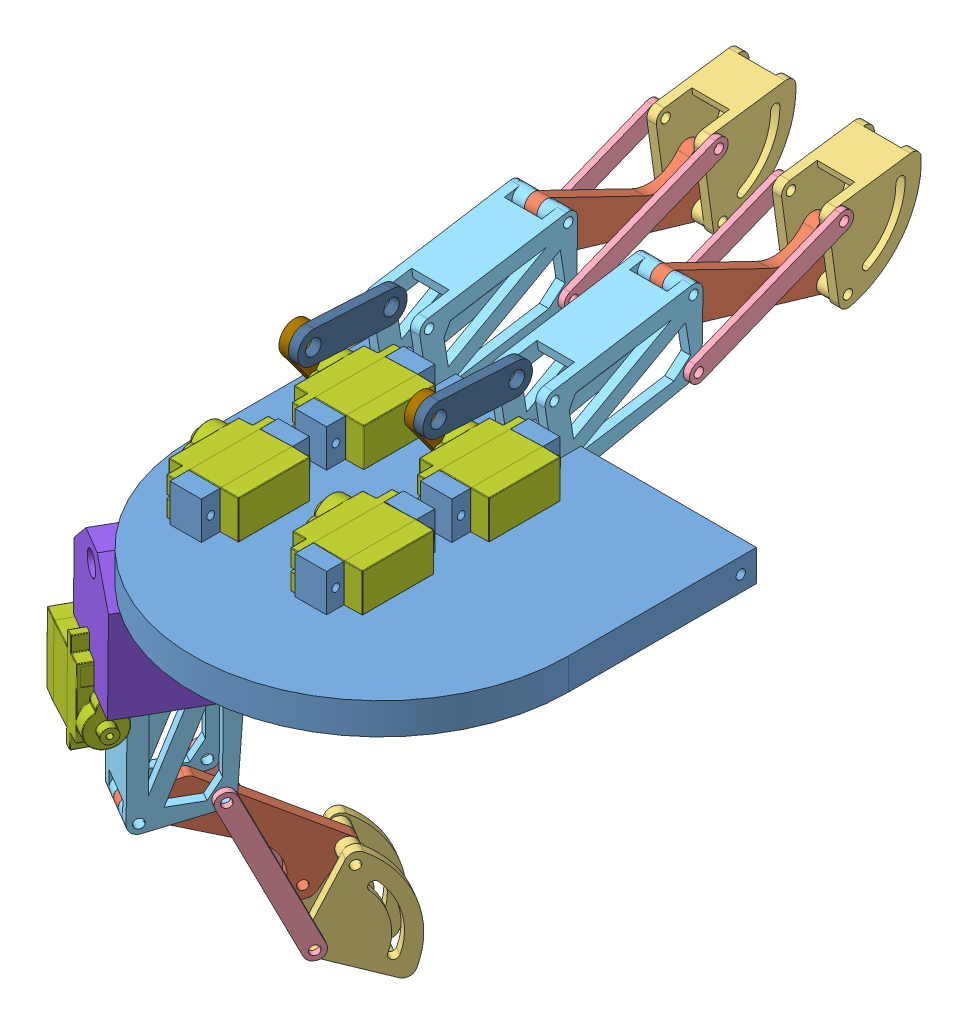
SolidWorks assembly hand, configuration Default. Lengths in mm.
Overall size (148.74 231.01 238.42).
30 component instances, 10 part files, 36 mates.
Components (placement in the parent):
- base-1: base [Default] at (16.5956 -11.2965 -4.4795) size (120 40 120)
- assembly-1: assembly [Default] at (10.0312 9.6394 -110.1816) x (0 -0.749901 -0.66155) z (1 0 0) size (97.15 111.4 22) (flexible)
  - [F1]ProximalPhalange-1: [F1]ProximalPhalange [Default] at (-2.4835 -4.9748 -0.4592) x (0.84704 0.531528 0) z (0 0 1) size (60.17 20 4)
  - [F1]DistalPhalange_Joint-1: [F1]DistalPhalange_Joint [Default] at (11.4723 33.8281 -7.4592) x (0.552506 0.833509 0) z (0 0 1) size (29.83 29.83 18)
  - [F1]MedialPhalange_Lever-1: [F1]MedialPhalange_Lever [Default] at (7.2551 11.1157 -9.4592) x (0.335009 0.942215 0) z (0 0 1) size (56 6 2)
  - [F1]MedialPhalange-1: [F1]MedialPhalange [Default] at (-40.1872 -36.8079 -7.4592) x (0.534366 0.845253 0) z (0 0 1) size (51 28 18)
  - [F1]MedialPhalange_Lever-2: [F1]MedialPhalange_Lever [Default] at (7.2551 11.1157 10.5408) x (0.335009 0.942215 0) z (0 0 1) size (56 6 2)
- assembly-2: assembly [Default] at (-29.9688 9.6845 -110.1674) x (0 -0.749313 -0.662216) z (1 0 0) size (97.15 111.4 22) (flexible)
  - [F1]ProximalPhalange-1: [F1]ProximalPhalange [Default] at (-2.4835 -4.9748 -0.4592) x (0.84704 0.531528 0) z (0 0 1) size (60.17 20 4)
  - [F1]DistalPhalange_Joint-1: [F1]DistalPhalange_Joint [Default] at (11.4723 33.8281 -7.4592) x (0.552506 0.833509 0) z (0 0 1) size (29.83 29.83 18)
  - [F1]MedialPhalange_Lever-1: [F1]MedialPhalange_Lever [Default] at (7.2551 11.1157 -9.4592) x (0.335009 0.942215 0) z (0 0 1) size (56 6 2)
  - [F1]MedialPhalange-1: [F1]MedialPhalange [Default] at (-40.1872 -36.8079 -7.4592) x (0.534366 0.845253 0) z (0 0 1) size (51 28 18)
  - [F1]MedialPhalange_Lever-2: [F1]MedialPhalange_Lever [Default] at (7.2551 11.1157 10.5408) x (0.335009 0.942215 0) z (0 0 1) size (56 6 2)
- assembly-3: assembly [Default] at (-37.6816 -101.2528 1.716) x (0.4097 -0.534158 -0.739474) z (-0.865687 0.027933 -0.499805) size (112.15 71.63 22) (flexible)
  - [F1]ProximalPhalange-1: [F1]ProximalPhalange [Default] at (-7.8164 -11.2497 -0.4592) x (0.999991 0.004269 0) z (0 0 1) size (60.17 20 4)
  - [F1]DistalPhalange_Joint-1: [F1]DistalPhalange_Joint [Default] at (38.2009 18.1184 -7.4592) x (0.992825 -0.119578 0) z (0 0 1) size (29.83 29.83 18)
  - [F1]MedialPhalange_Lever-1: [F1]MedialPhalange_Lever [Default] at (19.8503 1.1708 -9.4592) x (0.838815 0.544416 0) z (0 0 1) size (56 6 2)
  - [F1]MedialPhalange-1: [F1]MedialPhalange [Default] at (-40.1872 -36.8079 -7.4592) x (0.534366 0.845253 0) z (0 0 1) size (51 28 18)
  - [F1]MedialPhalange_Lever-2: [F1]MedialPhalange_Lever [Default] at (19.8503 1.1708 10.5408) x (0.838815 0.544416 0) z (0 0 1) size (56 6 2)
- servo_motor.ipt-2: servo_motor.ipt [Default] at (-13.0981 -31.2965 -49.4741) x (0 -1 0) z (-0.866025 0 -0.5) size (21.76 46 55)
- TowerPro SG92R Servo Motor-2: TowerPro SG92R Servo Motor [Default] at (-23.4044 4.7035 -34.6979) x (0 0 -1) z (0 1 0) size (32.49 29.58 12.43)
- TowerPro SG92R Servo Motor-3: TowerPro SG92R Servo Motor [Default] at (-23.4044 4.7035 5.3021) x (0 0 -1) z (0 1 0) size (32.49 29.58 12.43)
- TowerPro SG92R Servo Motor-4: TowerPro SG92R Servo Motor [Default] at (16.5956 4.7035 -34.6979) x (0 0 -1) z (0 1 0) size (32.49 29.58 12.43)
- TowerPro SG92R Servo Motor-5: TowerPro SG92R Servo Motor [Default] at (16.5956 4.7035 5.7389) x (0 0 -1) z (0 1 0) size (32.49 29.58 12.43)
- joint-1: joint [Default] at (-25.6367 -39.8449 -8.7932) x (-0.865687 0.027933 -0.499805) z (-0.5 0 0.866025) size (30 40.08 40)
- TowerPro SG92R Servo Motor-6: TowerPro SG92R Servo Motor [Default] at (-48.3775 -57.6939 22.4871) x (-0.024191 -0.99961 -0.013967) z (-0.477168 -0.000731 0.878812) size (32.49 29.58 12.43)
- bar1-1: bar1 [Default] at (-37.428 10.7264 -35.4787) x (0 0.803059 0.5959) z (1 0 0) size (25 10 3)
- bar1-2: bar1 [Default] at (2.572 10.7338 -35.4886) x (0 -0.804043 -0.594571) z (1 0 0) size (25 10 3)
- bar2-1: bar2 [Default] at (8.572 16.0948 -43.5114) x (0 0.053544 0.998566) z (-1 0 0) size (35 10 3)
- bar2-2: bar2 [Default] at (-31.428 16.0859 -43.4918) x (0 0.053078 0.99859) z (-1 0 0) size (35 10 3)
Mates (geometry in assembly coordinates):
- Concentric1: concentric aligned: cylinder of base-1 through (76.5956 -6.2965 -59.4795) axis (-1 0 0) radius 1.5; cylinder of assembly-1/[F1]MedialPhalange-1 through (5.572 -6.2965 -59.4795) axis (-1 0 0) radius 1.5
- Concentric2: concentric aligned: cylinder of base-1 through (-13.4044 4.7035 -48.7695) axis (-1 0 0) radius 1.25; cylinder of TowerPro SG92R Servo Motor-2 through (-18.2615 4.7035 -48.7695) axis (-1 0 0) radius 1.016
- Coincident1: coincident anti-aligned: plane of base-1 through (-23.4044 -11.2965 -4.4795) normal (-1 0 0); plane of TowerPro SG92R Servo Motor-2 through (-23.4044 4.7035 -34.6979) normal (1 0 0)
- Parallel1: parallel aligned: line of base-1 through (-23.4044 10.7035 -45.7695) axis (0 0 -1); line of TowerPro SG92R Servo Motor-2 through (-23.4044 10.7423 -45.8422) axis (0 0 -1)
- Concentric3: concentric aligned: cylinder of base-1 through (-13.4044 4.7035 -8.7695) axis (-1 0 0) radius 1.25; cylinder of TowerPro SG92R Servo Motor-3 through (-18.2615 4.7035 -8.7695) axis (-1 0 0) radius 1.016
- Coincident3: coincident anti-aligned: plane of base-1 through (-23.4044 -11.2965 35.5205) normal (-1 0 0); plane of TowerPro SG92R Servo Motor-3 through (-23.4044 4.7035 5.3021) normal (1 0 0)
- Parallel2: parallel anti-aligned: line of base-1 through (-23.4044 10.7035 -5.7695) axis (0 0 -1); line of TowerPro SG92R Servo Motor-3 through (-23.4044 10.7423 -5.8422) axis (0 0 1)
- Concentric4: concentric aligned: cylinder of base-1 through (26.5956 4.7035 -48.7695) axis (-1 0 0) radius 1.25; cylinder of TowerPro SG92R Servo Motor-4 through (21.7385 4.7035 -48.7695) axis (-1 0 0) radius 1.016
- Coincident5: coincident anti-aligned: plane of base-1 through (16.5956 -11.2965 -4.4795) normal (-1 0 0); plane of TowerPro SG92R Servo Motor-4 through (16.5956 4.7035 -34.6979) normal (1 0 0)
- Parallel3: parallel: line of base-1 through (16.5956 10.7035 -45.7695) axis (0 0 -1); plane of TowerPro SG92R Servo Motor-4 through (16.5956 10.7423 -34.6979) normal (-0.026177 0.999657 0)
- Concentric5: concentric aligned: cylinder of base-1 through (26.5956 4.7035 19.8105) axis (-1 0 0) radius 1.25; cylinder of TowerPro SG92R Servo Motor-5 through (21.7385 4.7035 19.8105) axis (-1 0 0) radius 1.016
- Coincident7: coincident anti-aligned: plane of base-1 through (16.5956 -11.2965 35.5205) normal (-1 0 0); plane of TowerPro SG92R Servo Motor-5 through (16.5956 4.7035 5.7389) normal (1 0 0)
- Parallel4: parallel anti-aligned: line of base-1 through (16.5956 10.7035 -5.7695) axis (0 0 -1); line of TowerPro SG92R Servo Motor-5 through (16.5956 10.7423 -5.4054) axis (0 0 1)
- Concentric6: concentric aligned: cylinder of base-1 through (76.5956 -6.2965 -59.4795) axis (-1 0 0) radius 1.5; cylinder of assembly-2/[F1]MedialPhalange-1 through (-34.428 -6.2965 -59.4795) axis (-1 0 0) radius 1.5
- Coincident9: coincident anti-aligned: plane of assembly-2/[F1]MedialPhalange-1 through (-34.428 2.2861 -100.1045) normal (1 0 0); plane of TowerPro SG92R Servo Motor-2 through (-34.428 4.7035 -34.6979) normal (-1 0 0)
- Coincident10: coincident anti-aligned: plane of assembly-1/[F1]MedialPhalange-1 through (5.572 2.2499 -100.1121) normal (1 0 0); plane of TowerPro SG92R Servo Motor-4 through (5.572 4.7035 -34.6979) normal (-1 0 0)
- Coincident11: coincident anti-aligned: plane of base-1 through (-36.9527 -29.2965 -31.4923) normal (-0.5 0 0.866025); plane of servo_motor.ipt-2 through (11.3653 -21.2965 -3.5959) normal (0.5 0 -0.866025)
- Coincident12: coincident anti-aligned: plane of base-1 through (16.5956 -11.2965 -4.4795) normal (0 -1 0); plane of servo_motor.ipt-2 through (21.9759 -11.2965 -29.2241) normal (0 1 0)
- Coincident13: coincident anti-aligned: plane of base-1 through (-26.8481 -29.2965 -25.6584) normal (0.866025 0 0.5); plane of servo_motor.ipt-2 through (-13.0981 -11.2965 -49.4741) normal (-0.866025 0 -0.5)
- Concentric7: concentric aligned: cylinder of servo_motor.ipt-2 through (-25.4379 -21.2965 -8.1011) axis (0.5 0 -0.866025) radius 3; cylinder of joint-1 through (-45.1879 -21.2965 26.1069) axis (0.5 0 -0.866025) radius 3.6171
- Coincident14: coincident anti-aligned: plane of servo_motor.ipt-2 through (-25.1879 -21.2965 -8.5341) normal (-0.5 0 0.866025); plane of joint-1 through (-25.6367 -39.8449 -8.7932) normal (0.5 0 -0.866025)
- Concentric8: concentric anti-aligned: cylinder of assembly-3/[F1]MedialPhalange-1 through (-28.699 -48.8112 -1.9896) axis (0.865687 -0.027933 0.499805) radius 1.5; cylinder of joint-1 through (-42.55 -48.3643 -9.9865) axis (-0.865687 0.027933 -0.499805) radius 2.5
- Distance1: distance = 1 mm aligned: plane of joint-1 through (-58.9849 -54.4201 18.1412) normal (-0.865687 0.027933 -0.499805); plane of assembly-3/[F1]MedialPhalange-1 through (-43.6875 -89.8495 -8.3339) normal (-0.865687 0.027933 -0.499805)
- Parallel5: parallel anti-aligned: plane of assembly-3/[F1]MedialPhalange-1 through (-28.6264 -45.8124 -1.9477) normal (0.024191 0.99961 0.013967); plane of joint-1 through (-33.0143 -55.2581 33.1354) normal (-0.024191 -0.99961 -0.013967)
- Coincident17: coincident anti-aligned: plane of assembly-3/[F1]MedialPhalange-1 through (-41.199 -48.8112 19.661) normal (-0.5 0 0.866025); plane of TowerPro SG92R Servo Motor-6 through (-45.496 -57.6895 17.1801) normal (0.5 0 -0.866025)
- Distance3: distance = 5 mm: line of TowerPro SG92R Servo Motor-6 through (-64.7414 -46.0403 20.5769) axis (-0.024191 -0.99961 -0.013967); plane of assembly-3/[F1]MedialPhalange-1 through (-43.6875 -89.8495 -8.3339) normal (-0.865687 0.027933 -0.499805)
- Concentric9: concentric anti-aligned: cylinder of TowerPro SG92R Servo Motor-2 through (-73.4847 4.7035 -39.9479) axis (1 0 0) radius 2.3813; cylinder of bar1-1 through (-34.428 4.7035 -39.9479) axis (-1 0 0) radius 2.5
- Coincident22: coincident anti-aligned: plane of TowerPro SG92R Servo Motor-2 through (-34.428 4.7035 -34.6979) normal (-1 0 0); plane of bar1-1 through (-34.428 4.7035 -39.9479) normal (1 0 0)
- Concentric10: concentric anti-aligned: cylinder of TowerPro SG92R Servo Motor-4 through (-33.4847 4.7035 -39.9479) axis (1 0 0) radius 2.3813; cylinder of bar1-2 through (5.572 4.7035 -39.9479) axis (-1 0 0) radius 2.5
- Coincident23: coincident aligned: plane of assembly-1/[F1]MedialPhalange-1 through (5.572 2.2499 -100.1121) normal (1 0 0); plane of bar1-2 through (5.572 16.7641 -31.0294) normal (1 0 0)
- Concentric11: concentric anti-aligned: cylinder of bar1-2 through (5.572 16.7641 -31.0294) axis (-1 0 0) radius 2.5; cylinder of bar2-1 through (5.572 16.7641 -31.0294) axis (1 0 0) radius 2.5
- Concentric12: concentric anti-aligned: cylinder of bar1-1 through (-34.428 16.7494 -31.0094) axis (-1 0 0) radius 2.5; cylinder of bar2-2 through (-34.428 16.7494 -31.0094) axis (1 0 0) radius 2.5
- Coincident24: coincident anti-aligned: plane of bar1-2 through (5.572 16.7641 -31.0294) normal (1 0 0); plane of bar2-1 through (5.572 15.4256 -55.9935) normal (-1 0 0)
- Coincident25: coincident anti-aligned: plane of bar1-1 through (-34.428 4.7035 -39.9479) normal (1 0 0); plane of bar2-2 through (-34.428 15.4224 -55.9742) normal (-1 0 0)
- Concentric13: concentric anti-aligned: cylinder of assembly-2/[F1]MedialPhalange-1 through (-34.428 15.4224 -55.9742) axis (-1 0 0) radius 1.5; cylinder of bar2-2 through (-34.428 15.4224 -55.9742) axis (1 0 0) radius 2.5
- Concentric14: concentric anti-aligned: cylinder of assembly-1/[F1]MedialPhalange-1 through (5.572 15.4256 -55.9935) axis (-1 0 0) radius 1.5; cylinder of bar2-1 through (5.572 15.4256 -55.9935) axis (1 0 0) radius 2.5
